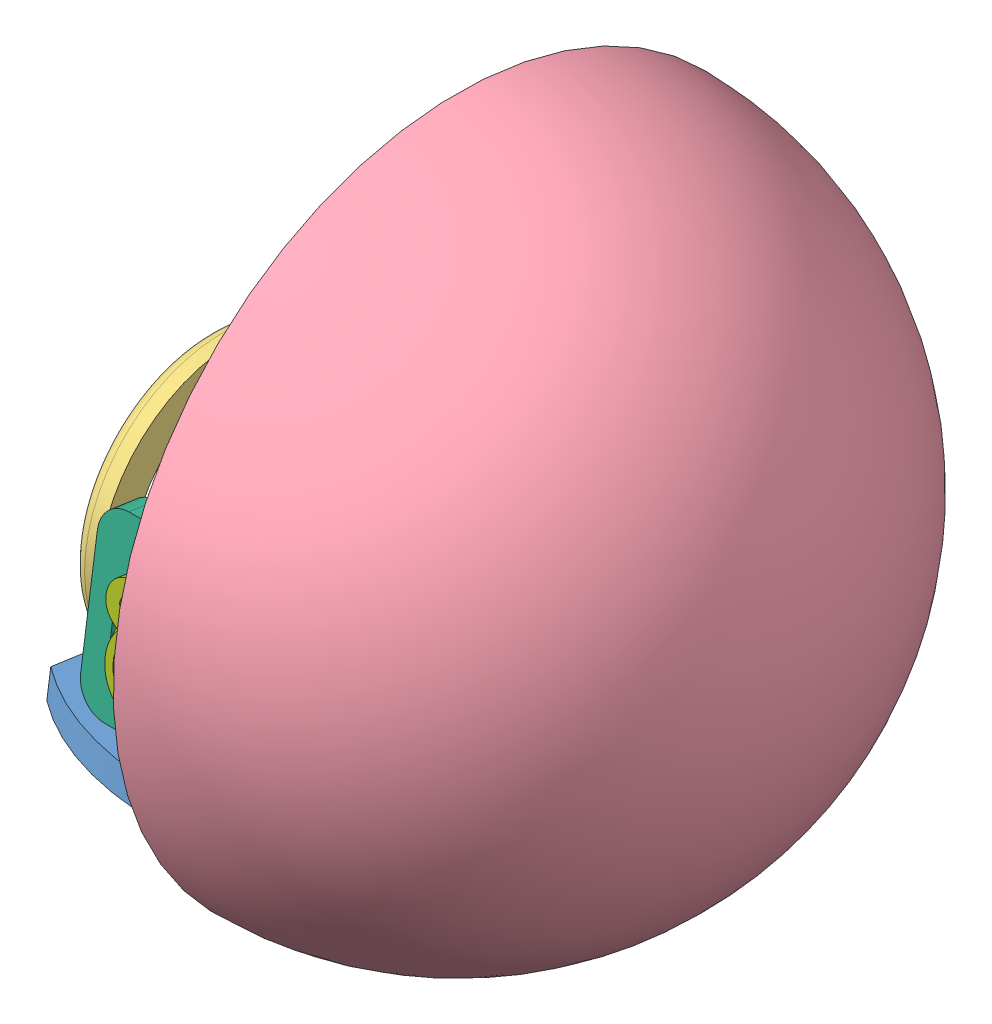
SolidWorks assembly MainCastor, configuration Default. Lengths in mm.
Overall size (84.01 140.15 140.15).
12 component instances, 8 part files, 21 mates.
Components (placement in the parent):
- Base-1: CBase [Default] at (37.3353 -161.0107 -76.7882) x (1 0 0) z (0 0.142722 0.989763) size (50 4 80)
- Motor Mount-1: CMotor Mount [Default] at (15.3353 -157.0516 -77.3591) x (0 -0.142722 -0.989763) z (1 0 0) size (15.67 16 4)
- Motor Mount-2: CMotor Mount [Default] at (55.3353 -157.0516 -77.3591) x (0 -0.142722 -0.989763) z (1 0 0) size (15.67 16 4)
- Wheel-1: CWheel [Default] at (67.3353 -150.1233 -78.3582) x (0 0.992904 -0.118917) z (0 -0.118917 -0.992904) size (40.79 4.01 40.79)
- Wheel-2: CWheel [Default] at (7.3353 -150.1233 -78.3582) x (0 -0.999972 -0.007423) z (0 0.007423 -0.999972) size (40.79 4.01 40.79)
- Outer Sphere-1: COuter Sphere [Default] at (37.3353 -95.9739 -49.3044) x (0 0.781433 0.62399) z (-1 0 0) size (100 100 50) (hidden)
- Outer Sphere-2: COuter Sphere [Default] at (37.3353 -174.8204 -110.8018) x (0 -0.795497 -0.605958) z (1 0 0) size (100 100 50)
- CastorSupport-1: CCastorSupport [Default] at (47.3353 -158.4417 -58.9725) x (0 -0.142722 -0.989763) z (1 0 0) size (17 17 4)
- CastorMount-1: CCastorMount [Default] at (54.8353 -127.8832 -50.2445) x (-1 0 0) z (0 0.142722 0.989763) size (35 25 4)
- CastorAss-1: CCastorAss [Default] at (37.8629 -136.9131 -43.6381) x (-0.953319 -0.298872 0.043097) z (0.301964 -0.94356 0.136059) size (22.95 11.75 20.75)
  - casterWheel_bottom_V2-2: CcasterWheel_bottom_V2 [Default] x (1 0 0) z (0 0 -1) size (22.95 10.25 20.75)
  - casterWheel-1: CcasterWheel [Default] at (0.5512 -5.5 0.2177) size (10 10 10)
Mates (geometry in assembly coordinates):
- Coincident1: coincident anti-aligned: plane of Base-1 through (19.3353 -157.0516 -77.3591) normal (-1 0 0); plane of Motor Mount-1 through (19.3353 -157.0516 -77.3591) normal (1 0 0)
- Coincident2: coincident aligned: plane of Base-1 through (37.3353 -161.0107 -76.7882) normal (0 -0.989763 0.142722); plane of Motor Mount-1 through (19.3353 -161.0107 -76.7882) normal (0 -0.989763 0.142722)
- Coincident3: coincident anti-aligned: plane of Base-1 through (37.3353 -156.7662 -75.3796) normal (0 -0.142722 -0.989763); plane of Motor Mount-1 through (19.3353 -156.7662 -75.3796) normal (0 0.142722 0.989763)
- Coincident4: coincident anti-aligned: plane of Base-1 through (59.3353 -157.0516 -77.3591) normal (-1 0 0); plane of Motor Mount-2 through (59.3353 -157.0516 -77.3591) normal (1 0 0)
- Coincident5: coincident anti-aligned: plane of Base-1 through (37.3353 -156.7662 -75.3796) normal (0 -0.142722 -0.989763); plane of Motor Mount-2 through (59.3353 -156.7662 -75.3796) normal (0 0.142722 0.989763)
- Coincident6: coincident aligned: plane of Base-1 through (37.3353 -161.0107 -76.7882) normal (0 -0.989763 0.142722); plane of Motor Mount-2 through (59.3353 -161.0107 -76.7882) normal (0 -0.989763 0.142722)
- Concentric1: concentric aligned: circle of Motor Mount-2; circle of Wheel-1
- Concentric2: concentric anti-aligned: circle of Motor Mount-1; circle of Wheel-2
- Distance1: distance = 68 mm anti-aligned: plane of Wheel-1 through (71.3353 -150.1233 -78.3582) normal (1 0 0); plane of Wheel-2 through (3.3353 -150.1233 -78.3582) normal (-1 0 0)
- Width1: width anti-aligned: plane of Wheel-2 through (7.3353 -150.1233 -78.3582) normal (1 0 0); plane of Base-1 through (67.3353 -150.1233 -78.3582) normal (-1 0 0); plane of Wheel-1 through (12.3353 -157.0516 -77.3591) normal (-1 0 0); plane of Base-1 through (62.3353 -157.0516 -77.3591) normal (1 0 0)
- Coincident7: coincident anti-aligned: plane of Outer Sphere-1 through (37.3353 -135.0456 -80.5039) normal (1 0 0)
- Coincident8: coincident anti-aligned: plane of Outer Sphere-1 through (37.3353 -135.0456 -80.5039) normal (1 0 0); plane of Outer Sphere-2 through (37.3353 -135.0456 -80.5039) normal (-1 0 0)
- Concentric4: concentric anti-aligned: circle of Outer Sphere-1; circle of Outer Sphere-2
- Tangent1: tangent: sphere of assembly; face of Wheel-1; sphere of Outer Sphere-2
- Coincident9: coincident anti-aligned: plane of Base-1 through (37.3353 -153.3408 -51.6253) normal (0 -0.142722 -0.989763); plane of CastorSupport-1 through (51.3353 -157.2999 -51.0544) normal (0 0.142722 0.989763)
- Coincident10: coincident anti-aligned: plane of Base-1 through (51.3353 -157.0516 -77.3591) normal (-1 0 0); plane of CastorSupport-1 through (51.3353 -158.4417 -58.9725) normal (1 0 0)
- Coincident11: coincident aligned: plane of Base-1 through (37.3353 -161.0107 -76.7882) normal (0 -0.989763 0.142722); plane of CastorSupport-1 through (51.3353 -158.4417 -58.9725) normal (0 -0.989763 0.142722)
- Coincident15: coincident anti-aligned: plane of CastorSupport-1 through (47.3353 -158.4417 -58.9725) normal (-1 0 0); plane of CastorMount-1 through (47.3353 -147.1075 -43.431) normal (1 0 0)
- Coincident17: coincident anti-aligned: plane of CastorSupport-1 through (51.3353 -141.6157 -61.3988) normal (0 0.989763 -0.142722); plane of CastorMount-1 through (51.3353 -139.1894 -44.5728) normal (0 -0.989763 0.142722)
- Coincident18: coincident aligned: plane of CastorSupport-1 through (51.3353 -156.0154 -42.1465) normal (0 0.142722 0.989763); plane of CastorMount-1 through (23.8353 -131.2713 -45.7146) normal (0 0.142722 0.989763)
- Coincident19: coincident anti-aligned: plane of CastorMount-1 through (23.8353 -131.2713 -45.7146) normal (0 0.142722 0.989763); plane of CastorAss-1/casterWheel_bottom_V2-2 through (37.8629 -137.0915 -44.8753) normal (0 -0.142722 -0.989763)
